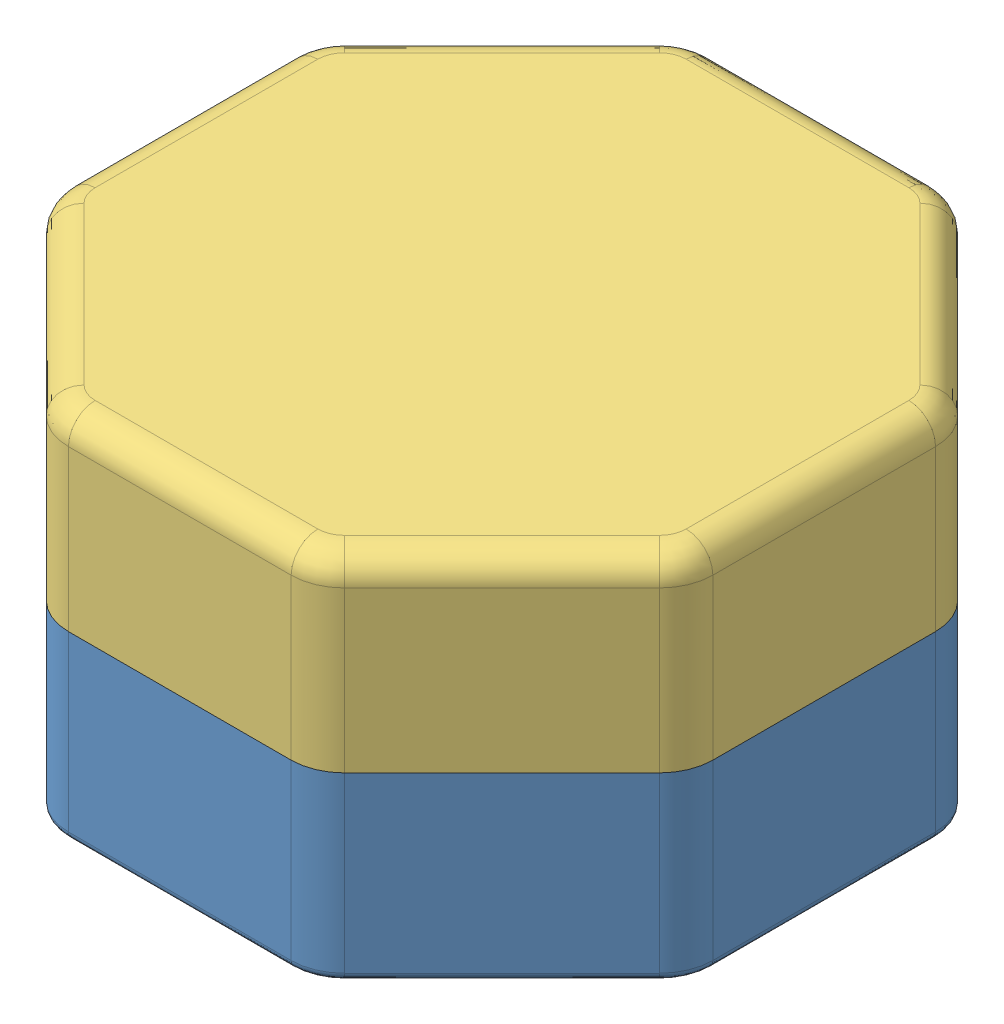
SolidWorks assembly Assem1, configuration Default. Lengths in mm.
Overall size (170.71 69 170.71).
79 component instances, 10 part files, 9 mates.
Components (placement in the parent):
- bottom_smart_object-1: bottom_smart_object [Default] at (43.5399 25.2944 107.5195) size (120.71 34 120.71)
- magnet-4: magnet [Default] at (-11.0816 63.2944 84.8946) x (-1 0 0) z (0 0 1) size (6 6 6)
- top_smart_object-1: top_smart_object [Default] at (43.5399 94.2944 107.5195) x (-0.707107 0 -0.707107) z (-0.707107 0 0.707107) size (120.71 37 120.71)
- smart_object_pcb.step-1: smart_object_pcb.step [Default] at (43.5399 57.6944 107.5195) x (-1 0 0) z (0 1 0) size (104.94 104.94 10.1)
  - PinSocket_1x19_P2.54mm_Vertical.step-1: PinSocket_1x19_P2.54mm_Vertical.step [Default] at (-17.98 -26.14 -0.05) x (1 0 0) z (0 0 -1) size (2.54 48.26 10.1)
    - SOLID.step-1: SOLID.step [Default] at origin size (2.54 48.26 10.1)
  - R_0805_2012Metric.step-1: R_0805_2012Metric.step [Default] at (1.282 6.861 1.65) x (0 1 0) z (0 0 1) size (2 1.2 0.45)
    - SOLID-0.step-1: SOLID-0.step [Default] at origin size (2 1.2 0.45)
  - R_0805_2012Metric.step-2: R_0805_2012Metric.step [Default] at (-0.512 3.1505 1.65) x (0 1 0) z (0 0 1) size (2 1.2 0.45)
    - SOLID-0.step-1: SOLID-0.step [Default] at origin size (2 1.2 0.45)
  - LMS1585AISX-3.3_NO.step-1: LMS1585AISX-3.3_NO.step [Default] at (-15.847 36.517 -0.05) x (0 -1 0) z (0 0 -1) size (10.16 15.24 4.55)
    - COMPOUND.step-1: COMPOUND.step [Default] at origin size (10.16 15.24 4.55)
  - C_0805_2012Metric.step-1: C_0805_2012Metric.step [Default] at (-15.3705 46.672 1.65) size (2 1.25 1.25)
    - SOLID-1.step-1: SOLID-1.step [Default] at origin size (2 1.25 1.25)
  - C_0805_2012Metric.step-2: C_0805_2012Metric.step [Default] at (-10.1675 46.637 1.65) size (2 1.25 1.25)
    - SOLID-1.step-1: SOLID-1.step [Default] at origin size (2 1.25 1.25)
  - PinSocket_1x04_P2.54mm_Vertical.step-1: PinSocket_1x04_P2.54mm_Vertical.step [Default] at (32.82 35.18 -0.05) x (-0.707107 -0.707107 0) z (0 0 -1) size (2.54 10.16 10.1)
    - SOLID-2.step-1: SOLID-2.step [Default] at origin size (2.54 10.16 10.1)
  - R_0805_2012Metric.step-3: R_0805_2012Metric.step [Default] at (-12.3925 11.28 1.65) x (-1 0 0) z (0 0 1) size (2 1.2 0.45)
    - SOLID-0.step-1: SOLID-0.step [Default] at origin size (2 1.2 0.45)
  - R_0805_2012Metric.step-4: R_0805_2012Metric.step [Default] at (-12.3925 13.53 1.65) x (-1 0 0) z (0 0 1) size (2 1.2 0.45)
    - SOLID-0.step-1: SOLID-0.step [Default] at origin size (2 1.2 0.45)
  - R_0805_2012Metric.step-5: R_0805_2012Metric.step [Default] at (3.393 6.8595 1.65) x (0 1 0) z (0 0 1) size (2 1.2 0.45)
    - SOLID-0.step-1: SOLID-0.step [Default] at origin size (2 1.2 0.45)
  - R_0805_2012Metric.step-6: R_0805_2012Metric.step [Default] at (16.82 14.98 1.65) x (-0.707107 -0.707107 0) z (0 0 1) size (2 1.2 0.45)
    - SOLID-0.step-1: SOLID-0.step [Default] at origin size (2 1.2 0.45)
  - C_0805_2012Metric.step-3: C_0805_2012Metric.step [Default] at (-3.41 1.718 1.65) x (0 1 0) z (0 0 1) size (2 1.25 1.25)
    - SOLID-1.step-1: SOLID-1.step [Default] at origin size (2 1.25 1.25)
  - C_0805_2012Metric.step-4: C_0805_2012Metric.step [Default] at (5.839 2.697 1.65) x (0 1 0) z (0 0 1) size (2 1.25 1.25)
    - SOLID-1.step-1: SOLID-1.step [Default] at origin size (2 1.25 1.25)
  - R_0805_2012Metric.step-7: R_0805_2012Metric.step [Default] at (1.62 19.2675 1.65) x (0 1 0) z (0 0 1) size (2 1.2 0.45)
    - SOLID-0.step-1: SOLID-0.step [Default] at origin size (2 1.2 0.45)
  - R_0805_2012Metric.step-8: R_0805_2012Metric.step [Default] at (-0.63 19.23 1.65) x (0 1 0) z (0 0 1) size (2 1.2 0.45)
    - SOLID-0.step-1: SOLID-0.step [Default] at origin size (2 1.2 0.45)
  - R_0805_2012Metric.step-9: R_0805_2012Metric.step [Default] at (-2.88 19.23 1.65) x (0 1 0) z (0 0 1) size (2 1.2 0.45)
    - SOLID-0.step-1: SOLID-0.step [Default] at origin size (2 1.2 0.45)
  - R_0805_2012Metric.step-10: R_0805_2012Metric.step [Default] at (-12.3925 15.78 1.65) x (-1 0 0) z (0 0 1) size (2 1.2 0.45)
    - SOLID-0.step-1: SOLID-0.step [Default] at origin size (2 1.2 0.45)
  - R_0805_2012Metric.step-11: R_0805_2012Metric.step [Default] at (-22.4925 2.13 1.65) x (-1 0 0) z (0 0 1) size (2 1.2 0.45)
    - SOLID-0.step-1: SOLID-0.step [Default] at origin size (2 1.2 0.45)
  - R_0805_2012Metric.step-12: R_0805_2012Metric.step [Default] at (-22.4925 -0.12 1.65) x (-1 0 0) z (0 0 1) size (2 1.2 0.45)
    - SOLID-0.step-1: SOLID-0.step [Default] at origin size (2 1.2 0.45)
  - R_0805_2012Metric.step-13: R_0805_2012Metric.step [Default] at (-22.4925 -2.37 1.65) x (-1 0 0) z (0 0 1) size (2 1.2 0.45)
    - SOLID-0.step-1: SOLID-0.step [Default] at origin size (2 1.2 0.45)
  - R_0805_2012Metric.step-14: R_0805_2012Metric.step [Default] at (-13.5425 -10.62 1.65) x (-1 0 0) z (0 0 1) size (2 1.2 0.45)
    - SOLID-0.step-1: SOLID-0.step [Default] at origin size (2 1.2 0.45)
  - R_0805_2012Metric.step-15: R_0805_2012Metric.step [Default] at (-13.5425 -12.87 1.65) x (-1 0 0) z (0 0 1) size (2 1.2 0.45)
    - SOLID-0.step-1: SOLID-0.step [Default] at origin size (2 1.2 0.45)
  - R_0805_2012Metric.step-16: R_0805_2012Metric.step [Default] at (-13.5425 -15.12 1.65) x (-1 0 0) z (0 0 1) size (2 1.2 0.45)
    - SOLID-0.step-1: SOLID-0.step [Default] at origin size (2 1.2 0.45)
  - R_0805_2012Metric.step-17: R_0805_2012Metric.step [Default] at (-3 6.209 1.65) size (2 1.2 0.45)
    - SOLID-0.step-1: SOLID-0.step [Default] at origin size (2 1.2 0.45)
  - R_0805_2012Metric.step-18: R_0805_2012Metric.step [Default] at (13.62 17.98 1.65) x (-0.707107 -0.707107 0) z (0 0 1) size (2 1.2 0.45)
    - SOLID-0.step-1: SOLID-0.step [Default] at origin size (2 1.2 0.45)
  - R_0805_2012Metric.step-19: R_0805_2012Metric.step [Default] at (15.1748 16.5348 1.65) x (-0.707107 -0.707107 0) z (0 0 1) size (2 1.2 0.45)
    - SOLID-0.step-1: SOLID-0.step [Default] at origin size (2 1.2 0.45)
  - R_0805_2012Metric.step-20: R_0805_2012Metric.step [Default] at (19.2 1.84 1.65) x (-1 0 0) z (0 0 1) size (2 1.2 0.45)
    - SOLID-0.step-1: SOLID-0.step [Default] at origin size (2 1.2 0.45)
  - R_0805_2012Metric.step-21: R_0805_2012Metric.step [Default] at (19.2 -0.41 1.65) x (-1 0 0) z (0 0 1) size (2 1.2 0.45)
    - SOLID-0.step-1: SOLID-0.step [Default] at origin size (2 1.2 0.45)
  - R_0805_2012Metric.step-22: R_0805_2012Metric.step [Default] at (19.2 -2.66 1.65) x (-1 0 0) z (0 0 1) size (2 1.2 0.45)
    - SOLID-0.step-1: SOLID-0.step [Default] at origin size (2 1.2 0.45)
  - R_0805_2012Metric.step-23: R_0805_2012Metric.step [Default] at (21.268 -13.388 1.65) x (-0.707107 0.707107 0) z (0 0 1) size (2 1.2 0.45)
    - SOLID-0.step-1: SOLID-0.step [Default] at origin size (2 1.2 0.45)
  - R_0805_2012Metric.step-24: R_0805_2012Metric.step [Default] at (19.668 -14.988 1.65) x (-0.707107 0.707107 0) z (0 0 1) size (2 1.2 0.45)
    - SOLID-0.step-1: SOLID-0.step [Default] at origin size (2 1.2 0.45)
  - R_0805_2012Metric.step-25: R_0805_2012Metric.step [Default] at (18.068 -16.588 1.65) x (-0.707107 0.707107 0) z (0 0 1) size (2 1.2 0.45)
    - SOLID-0.step-1: SOLID-0.step [Default] at origin size (2 1.2 0.45)
  - R_0805_2012Metric.step-26: R_0805_2012Metric.step [Default] at (2.62 -18.9575 1.65) x (0 1 0) z (0 0 1) size (2 1.2 0.45)
    - SOLID-0.step-1: SOLID-0.step [Default] at origin size (2 1.2 0.45)
  - R_0805_2012Metric.step-27: R_0805_2012Metric.step [Default] at (0.37 -18.9575 1.65) x (0 1 0) z (0 0 1) size (2 1.2 0.45)
    - SOLID-0.step-1: SOLID-0.step [Default] at origin size (2 1.2 0.45)
  - R_0805_2012Metric.step-28: R_0805_2012Metric.step [Default] at (-1.88 -18.9575 1.65) x (0 1 0) z (0 0 1) size (2 1.2 0.45)
    - SOLID-0.step-1: SOLID-0.step [Default] at origin size (2 1.2 0.45)
  - PinSocket_1x19_P2.54mm_Vertical.step-2: PinSocket_1x19_P2.54mm_Vertical.step [Default] at (-41.58 19.56 -0.05) x (-1 0 0) z (0 0 -1) size (2.54 48.26 10.1)
    - SOLID.step-1: SOLID.step [Default] at origin size (2.54 48.26 10.1)
  - PinSocket_1x09_P2.54mm_Vertical.step-1: PinSocket_1x09_P2.54mm_Vertical.step [Default] at (47.22 8.52 -0.05) x (-1 0 0) z (0 0 -1) size (2.54 22.86 10.1)
    - SOLID-3.step-1: SOLID-3.step [Default] at origin size (2.54 22.86 10.1)
  - COMPOUND-4.step-1: COMPOUND-4.step [Default] at origin size (104.94 104.94 1.6)
Mates (geometry in assembly coordinates):
- Concentric1: concentric: cylinder of assembly; cylinder of assembly; cylinder of magnet-4 through (-11.0816 57.2944 84.8946) axis (0 1 0) radius 3; cylinder of top_smart_object-1 through (-11.0816 59.2944 84.8946) axis (0 1 0) radius 3
- Coincident1: coincident: circle of ?; circle of ?
- Coincident3: coincident: plane of assembly; plane of assembly; plane of top_smart_object-1 through (43.5399 59.2944 107.5195) normal (0 -1 0); plane of smart_object_pcb.step-1/COMPOUND-4.step-1 through (43.5399 59.2944 107.5195) normal (0 1 0)
- Concentric2: concentric: circle of assembly; circle of assembly; circle of top_smart_object-1; circle of smart_object_pcb.step-1/COMPOUND-4.step-1
- Concentric4: concentric: cylinder of assembly; cylinder of assembly; cylinder of magnet-4 through (-11.0816 57.2944 84.8946) axis (0 1 0) radius 3; cylinder of top_smart_object-1 through (-11.0816 59.2944 84.8946) axis (0 1 0) radius 3
- Coincident4: coincident: plane of assembly; plane of assembly; plane of magnet-4 through (-11.0816 63.2944 84.8946) normal (0 1 0); plane of top_smart_object-1 through (-6.8155 63.2944 128.3774) normal (0 -1 0)
- Coincident5: coincident: plane of assembly; plane of assembly; plane of bottom_smart_object-1 through (43.5399 59.2944 107.5195) normal (0 1 0); plane of top_smart_object-1 through (43.5399 59.2944 107.5195) normal (0 -1 0)
- Concentric5: concentric: circle of assembly; circle of assembly; circle of bottom_smart_object-1; circle of smart_object_pcb.step-1/COMPOUND-4.step-1
- Concentric6: concentric: cylinder of assembly; cylinder of assembly; cylinder of bottom_smart_object-1 through (-11.0816 57.2944 84.8946) axis (0 1 0) radius 3.25; cylinder of magnet-4 through (-11.0816 57.2944 84.8946) axis (0 1 0) radius 3
